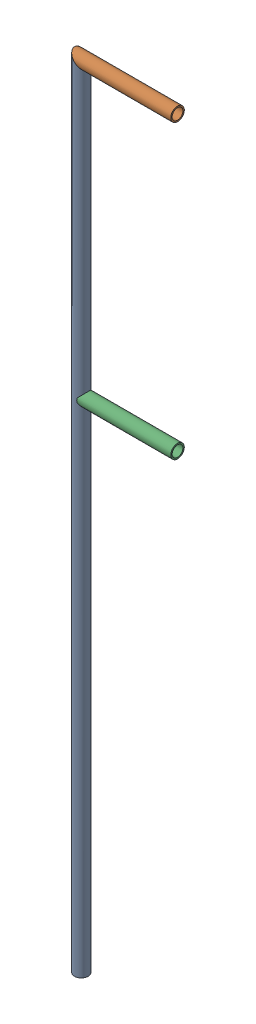
SolidWorks assembly GE-15012_ASM, configuration Default. Lengths in mm.
Overall size (254 1968.5 33.4).
3 component instances, 3 part files, 0 mates.
Components (placement in the parent):
- GE-15012-01-1: GE-15012-01 [Default] at origin size (33.4 1968.5 33.4)
- GE-15012-02-1: GE-15012-02 [Default] at (-16.7005 1951.7995 0) size (254 33.4 33.4)
- GE-15012-03-1: GE-15012-03 [Default] at (5.5245 1231.9 0) size (231.78 33.4 33.4)
